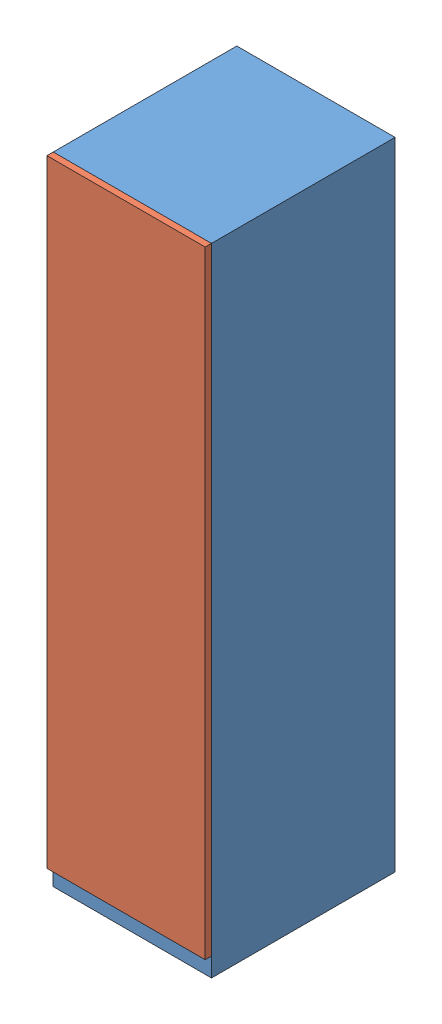
SolidWorks assembly PAX-L, configuration Standard. Lengths in mm.
Overall size (500 2010 600).
7 component instances, 5 part files, 18 mates.
Components (placement in the parent):
- Pax-Korpus-Kleiderschrank-1: Pax-Korpus-Kleiderschrank [Standard] at (-317.8358 -932.7261 1650) size (500 2010 580)
- BALLSTAD-Tür-1: BALLSTAD-Tür [Standard] at (-317.8358 102.2739 1940) size (500 1950 20)
- KOMPLEMENT-Regalbode-1: KOMPLEMENT-Regalbode [Standard] at (-317.8358 -752.7261 1655) size (480 10 570)
- KOMPLIMENT-Schublade-1: KOMPLIMENT-Schublade [Standard] at (-317.8358 -732.7261 1655) size (480 160 570)
- KOMPLEMENT-Regalbode-2: KOMPLEMENT-Regalbode [Standard] at (-317.8358 -562.7261 1655) size (480 10 570)
- KOMPLEMENT-Regalbode-3: KOMPLEMENT-Regalbode [Standard] at (-317.8358 907.2739 1655) size (480 10 570)
- KOMPLEMENT-Kleiderstange-1: KOMPLEMENT-Kleiderstange [Standard] at (-557.8358 692.2739 1660) size (480 50 30)
Mates (geometry in assembly coordinates):
- Deckungsgleich1: coincident anti-aligned: plane of BALLSTAD-Tür-1 through (-317.8358 102.2739 1940) normal (0 0 -1); plane of Pax-Korpus-Kleiderschrank-1 through (-567.8358 -922.7261 1940) normal (0 0 1)
- Deckungsgleich2: coincident aligned: plane of BALLSTAD-Tür-1 through (-567.8358 -872.7261 1960) normal (-1 0 0); plane of Pax-Korpus-Kleiderschrank-1 through (-567.8358 -922.7261 1940) normal (-1 0 0)
- Deckungsgleich3: coincident aligned: plane of BALLSTAD-Tür-1 through (-567.8358 1077.2739 1960) normal (0 1 0); plane of Pax-Korpus-Kleiderschrank-1 through (-317.8358 1077.2739 1650) normal (0 1 0)
- Deckungsgleich4: coincident anti-aligned: plane of Pax-Korpus-Kleiderschrank-1 through (-557.8358 1067.2739 1370) normal (0 0 1); plane of KOMPLEMENT-Regalbode-1 through (-557.8358 -742.7261 1370) normal (0 0 -1)
- Deckungsgleich5: coincident anti-aligned: plane of Pax-Korpus-Kleiderschrank-1 through (-557.8358 1067.2739 1940) normal (1 0 0); plane of KOMPLEMENT-Regalbode-1 through (-557.8358 -742.7261 1940) normal (-1 0 0)
- Abstand1: distance = 120 mm anti-aligned: plane of KOMPLEMENT-Regalbode-1 through (-317.8358 -752.7261 1655) normal (0 -1 0); plane of Pax-Korpus-Kleiderschrank-1 through (-317.8358 -872.7261 1650) normal (0 1 0)
- Deckungsgleich7: coincident: plane of Pax-Korpus-Kleiderschrank-1 through (-557.8358 1067.2739 1370) normal (0 0 1); plane of KOMPLIMENT-Schublade-1 through (-557.8358 -722.7261 1370) normal (0 0 -1)
- Deckungsgleich8: coincident anti-aligned: plane of Pax-Korpus-Kleiderschrank-1 through (-557.8358 1067.2739 1940) normal (1 0 0); plane of KOMPLIMENT-Schublade-1 through (-557.8358 -722.7261 1940) normal (-1 0 0)
- Abstand2: distance = 10 mm: plane of KOMPLEMENT-Regalbode-1 through (-317.8358 -742.7261 1655) normal (0 1 0); plane of KOMPLIMENT-Schublade-1 through (-317.8358 -732.7261 1655) normal (0 -1 0)
- Deckungsgleich10: coincident: plane of Pax-Korpus-Kleiderschrank-1 through (-557.8358 1067.2739 1940) normal (1 0 0); plane of KOMPLEMENT-Regalbode-2 through (-557.8358 -552.7261 1940) normal (-1 0 0)
- Deckungsgleich11: coincident anti-aligned: plane of Pax-Korpus-Kleiderschrank-1 through (-557.8358 1067.2739 1370) normal (0 0 1); plane of KOMPLEMENT-Regalbode-2 through (-557.8358 -552.7261 1370) normal (0 0 -1)
- Abstand3: distance = 10 mm anti-aligned: plane of KOMPLIMENT-Schublade-1 through (-317.8358 -572.7261 1655) normal (0 1 0); plane of KOMPLEMENT-Regalbode-2 through (-317.8358 -562.7261 1655) normal (0 -1 0)
- Deckungsgleich13: coincident: plane of Pax-Korpus-Kleiderschrank-1 through (-557.8358 1067.2739 1940) normal (1 0 0); plane of KOMPLEMENT-Regalbode-3 through (-557.8358 917.2739 1940) normal (-1 0 0)
- Deckungsgleich14: coincident anti-aligned: plane of Pax-Korpus-Kleiderschrank-1 through (-557.8358 1067.2739 1370) normal (0 0 1); plane of KOMPLEMENT-Regalbode-3 through (-557.8358 917.2739 1370) normal (0 0 -1)
- Abstand4: distance = 150 mm anti-aligned: plane of KOMPLEMENT-Regalbode-3 through (-317.8358 917.2739 1655) normal (0 1 0); plane of Pax-Korpus-Kleiderschrank-1 through (-317.8358 1067.2739 1650) normal (0 -1 0)
- Deckungsgleich16: coincident anti-aligned: plane of Pax-Korpus-Kleiderschrank-1 through (-557.8358 1067.2739 1940) normal (1 0 0); plane of KOMPLEMENT-Kleiderstange-1 through (-557.8358 692.2739 1660) normal (-1 0 0)
- Abstand5: distance = 275 mm anti-aligned: plane of KOMPLEMENT-Kleiderstange-1 through (-537.8358 657.2739 1645) normal (0 0 -1); plane of Pax-Korpus-Kleiderschrank-1 through (-557.8358 1067.2739 1370) normal (0 0 1)
- Abstand6: distance = 200 mm anti-aligned: plane of KOMPLEMENT-Kleiderstange-1 through (-537.8358 707.2739 1645) normal (0 1 0); plane of KOMPLEMENT-Regalbode-3 through (-317.8358 907.2739 1655) normal (0 -1 0)
